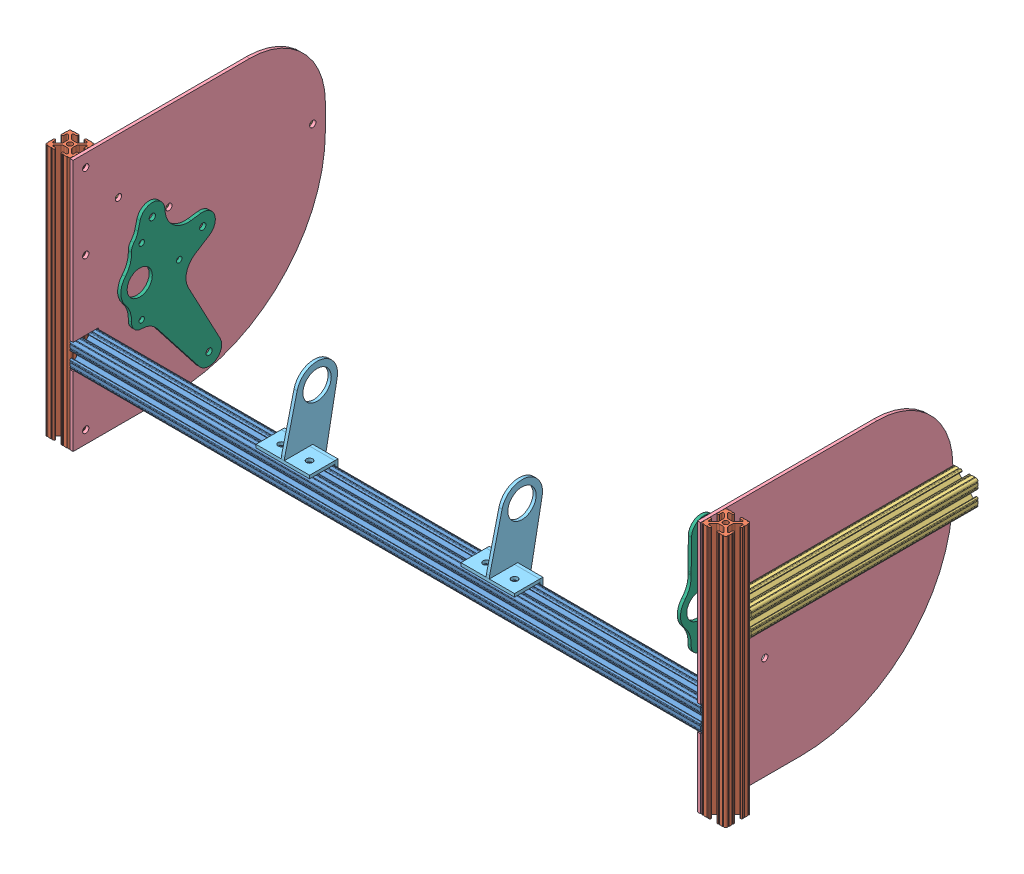
SolidWorks assembly Climber Test, configuration Default. Lengths in mm.
Overall size (685.8 254 254).
11 component instances, 6 part files, 15 mates.
Components (placement in the parent):
- Cross Brace Climber-1: Cross Brace Climber [Default] at origin size (635 25.4 25.4)
- Brace Vert Climber-1: Brace Vert Climber [Default] at (-330.2 44.45 0) size (25.4 254 25.4)
- Brace Hori Climber-1: Brace Hori Climber [Default] at (-330.2 82.55 -127) size (25.4 25.4 228.6)
- Quarter Panel-1: Quarter Panel [Default] at (-317.5 -82.55 12.7) size (3.17 254 254)
- Support Mid 2-1: Support Mid 2 [Default] at (-103.1875 65.475 -20.225) size (53.98 98.81 53.56)
- Mount Plate Motor-1: Mount Plate Motor [Left] at (-283.3687 65.475 -20.225) x (-1 0 0) z (0 0 -1) size (3.28 171.45 101.6)
- Support Mid 2-2: Support Mid 2 [Default] at (103.1875 65.475 -20.225) size (53.98 98.81 53.56)
- Mount Plate Motor-2: Mount Plate Motor [Right] at (280.1938 65.475 -20.225) x (-1 0 0) z (0 0 -1) size (3.17 133.35 127)
- Quarter Panel-2: Quarter Panel [Right] at (314.325 -82.55 12.7) size (3.17 254 254)
- Brace Hori Climber-2: Brace Hori Climber [Default] at (330.2 82.55 -127) x (-1 0 0) z (0 0 -1) size (25.4 25.4 228.6)
- Brace Vert Climber-2: Brace Vert Climber [Default] at (330.2 44.45 0) x (-1 0 0) z (0 0 -1) size (25.4 254 25.4)
Mates (geometry in assembly coordinates):
- Coincident1: coincident anti-aligned: plane of Cross Brace Climber-1 through (317.5 6.3331 -12.7) normal (0 0 -1); plane of Quarter Panel-1 through (-317.5 12.7 -12.7) normal (0 0 1)
- Coincident2: coincident anti-aligned: plane of Cross Brace Climber-1 through (317.5 12.7 -9.5504) normal (0 1 0); plane of Quarter Panel-1 through (-317.5 12.7 12.7) normal (0 -1 0)
- Coincident3: coincident anti-aligned: plane of Brace Vert Climber-1 through (-317.5 171.45 -6.3331) normal (1 0 0); plane of Quarter Panel-1 through (-317.5 -82.55 12.7) normal (-1 0 0)
- Coincident4: coincident aligned: plane of Cross Brace Climber-1 through (317.5 9.5504 12.7) normal (0 0 1); plane of Brace Vert Climber-1 through (-323.8669 171.45 12.7) normal (0 0 1)
- Coincident5: coincident anti-aligned: plane of Cross Brace Climber-1 through (-317.5 -12.7 -5.8251) normal (-1 0 0); plane of Brace Vert Climber-1 through (-317.5 171.45 9.5504) normal (1 0 0)
- Coincident6: coincident aligned: plane of Brace Vert Climber-1 through (-317.5 -82.55 -5.8251) normal (0 -1 0); plane of Quarter Panel-1 through (-314.325 -82.55 12.7) normal (0 -1 0)
- Coincident7: coincident anti-aligned: plane of Brace Vert Climber-1 through (-320.6496 171.45 -12.7) normal (0 0 -1); plane of Brace Hori Climber-1 through (-317.5 88.3751 -12.7) normal (0 0 1)
- Coincident8: coincident anti-aligned: plane of Brace Hori Climber-1 through (-317.5 88.8831 -12.7) normal (1 0 0); plane of Quarter Panel-1 through (-317.5 -82.55 12.7) normal (-1 0 0)
- Distance1: distance = 152.4 mm aligned: plane of Brace Hori Climber-1 through (-339.7504 69.85 -12.7) normal (0 -1 0); plane of Quarter Panel-1 through (-314.325 -82.55 12.7) normal (0 -1 0)
- Coincident10: coincident anti-aligned: plane of Cross Brace Climber-1 through (317.5 12.7 -9.5504) normal (0 1 0); plane of Support Mid 2-1 through (-130.175 12.7 12.7) normal (0 -1 0)
- Coincident11: coincident anti-aligned: plane of Cross Brace Climber-1 through (317.5 6.3331 -12.7) normal (0 0 -1); plane of Support Mid 2-1 through (-103.1875 65.475 -12.7) normal (0 0 1)
- Concentric1: concentric aligned: cylinder of Support Mid 2-1 through (-101.6 65.475 -20.225) axis (-1 0 0) radius 14.2875; cylinder of Mount Plate Motor-1 through (-259.9813 65.475 -20.225) axis (-1 0 0) radius 12.7
- Parallel1: parallel aligned: plane of Cross Brace Climber-1 through (317.5 12.7 -9.5504) normal (0 1 0); plane of Mount Plate Motor-1
- Distance2: distance = 203.2 mm anti-aligned: plane of Support Mid 2-1 through (-101.6 65.475 -20.225) normal (1 0 0); plane of Support Mid 2-2 through (101.6 65.475 -20.225) normal (-1 0 0)
- Distance3: distance = 30.9563 mm anti-aligned: plane of Quarter Panel-1 through (-314.325 -82.55 12.7) normal (1 0 0); plane of Mount Plate Motor-1 through (-283.3687 65.475 -20.225) normal (-1 0 0)
